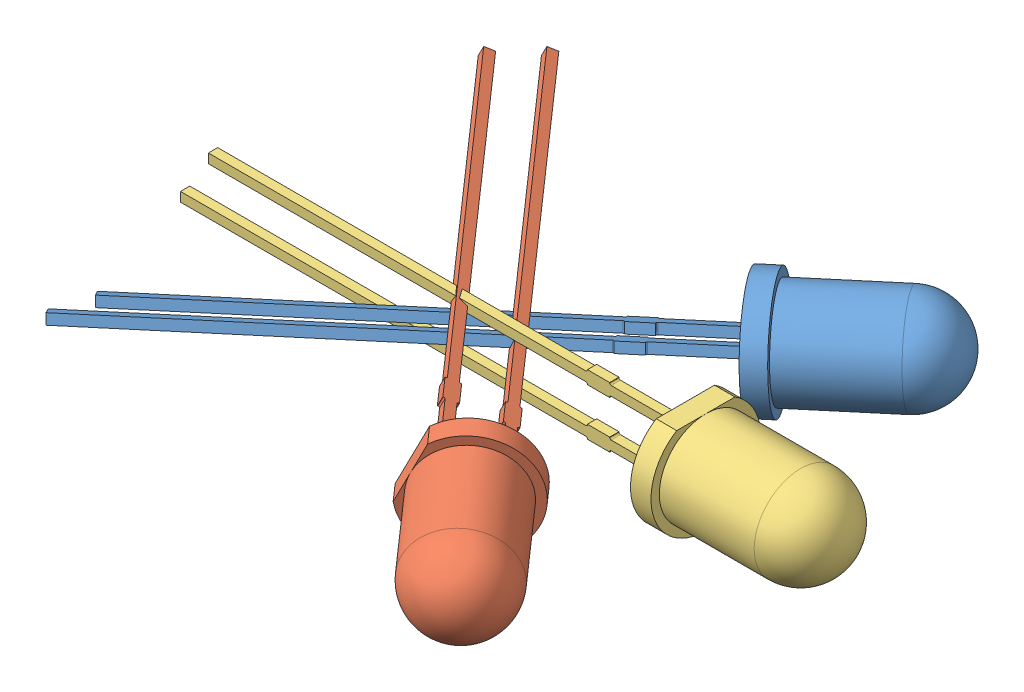
SolidWorks assembly Led Montaj, configuration Varsayılan. Lengths in mm.
Overall size (35.64 9.89 31.55).
3 component instances, 3 part files, 0 mates.
Components (placement in the parent):
- Led Lamp 5 mm 1(2)-1: Led Lamp 5 mm 1(2) [Default] at (27.9466 10.4268 14.9759) x (0.803139 0.04588 -0.594023) z (-0.217941 0.950553 -0.221246) size (35.6 5.45 5.9)
- Led Lamp 5 mm 2-1: Led Lamp 5 mm 2 [Default] at (26.7615 10.3381 28.9558) x (0.656537 -0.053384 0.752402) z (-0.34958 -0.905434 0.240798) size (35.6 5.45 5.9)
- Led Lamp 5 mm 3-1: Led Lamp 5 mm 3 [Default] at (31.2757 10.1695 21.8815) size (35.6 5.45 5.9)
